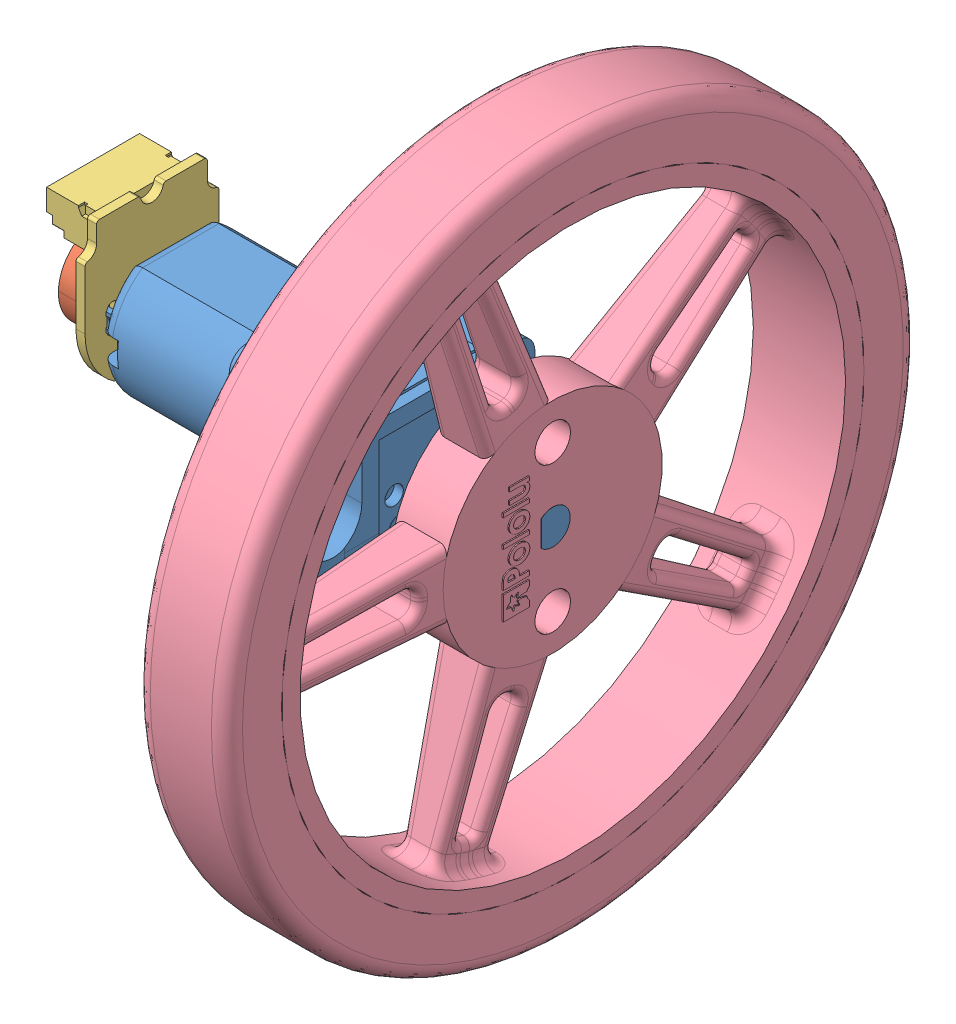
SolidWorks assembly MotorWheelAssembly, configuration Default. Lengths in mm.
Overall size (41.61 60 60).
4 component instances, 4 part files, 8 mates.
Components (placement in the parent):
- MicroMetalGearMotor-1: MicroMetalGearMotor [Default] at (14.4154 21.7011 29.4507) size (39.27 11.71 26.51)
- MagneticEncoderDisk-1: MagneticEncoderDisk [Default] at (-6.372 21.7011 29.4507) x (0 -0.027919 -0.99961) z (1 0 0) size (7.65 7.65 2)
- MagneticEncoderTopEntry-1: MagneticEncoderTopEntry [Default] at (-2.0846 21.7011 29.4507) x (0 0 -1) z (-1 0 0) size (11.6 12.8 5.11)
- pololu-wheel-60x8mm-black-1: pololu-wheel-60x8mm-black [Default] at (30.4154 21.7011 29.4507) x (1 0 0) z (0 -1 0) size (11 60 60)
Mates (geometry in assembly coordinates):
- Concentric1: concentric anti-aligned: cylinder of MicroMetalGearMotor-1 through (-6.5846 21.7011 29.4507) axis (1 0 0) radius 0.5; cylinder of MagneticEncoderDisk-1 through (-4.372 21.7011 29.4507) axis (-1 0 0) radius 0.5
- Concentric2: concentric aligned: cylinder of MicroMetalGearMotor-1 through (-6.5846 21.7011 29.4507) axis (1 0 0) radius 0.5; cylinder of MagneticEncoderTopEntry-1 through (-2.872 21.7011 29.4507) axis (1 0 0) radius 0.8128
- Parallel1: parallel aligned: plane of MicroMetalGearMotor-1 through (-0.5846 26.7011 32.7674) normal (0 1 0); plane of MagneticEncoderTopEntry-1 through (-2.872 29.7011 28.226) normal (0 1 0)
- Coincident2: coincident anti-aligned: circle of MicroMetalGearMotor-1; plane of MagneticEncoderTopEntry-1 through (-2.0846 17.1511 30.6755) normal (1 0 0)
- Distance1: distance = 1.5 mm anti-aligned: plane of MagneticEncoderDisk-1 through (-4.372 21.7011 29.4507) normal (1 0 0); plane of MagneticEncoderTopEntry-1 through (-2.872 17.1511 30.6755) normal (-1 0 0)
- Concentric3: concentric: cylinder of MicroMetalGearMotor-1 through (33.4154 21.7011 29.4507) axis (-1 0 0) radius 1.5; cylinder of pololu-wheel-60x8mm-black-1 through (34.4154 21.7011 29.4507) axis (-1 0 0) radius 1.5
- Coincident3: coincident: plane of MicroMetalGearMotor-1 through (33.4154 22.8191 30.4507) normal (0 0 1); plane of pololu-wheel-60x8mm-black-1 through (34.4154 22.8191 30.4507) normal (0 0 -1)
- Coincident4: coincident anti-aligned: plane of MicroMetalGearMotor-1 through (23.4154 16.7011 35.4507) normal (1 0 0); plane of pololu-wheel-60x8mm-black-1 through (23.4154 21.7011 29.4507) normal (-1 0 0)
